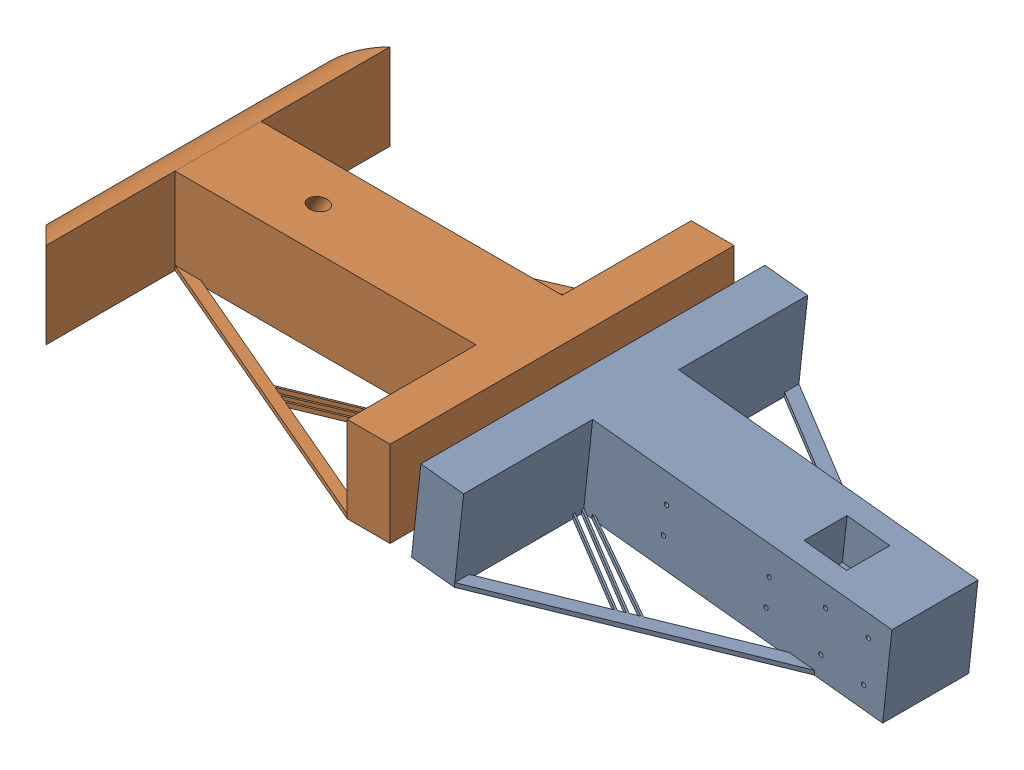
SolidWorks assembly Chassis_Assembly, configuration Default. Lengths in mm.
Overall size (1121.91 183.54 508).
5 component instances, 4 part files, 8 mates.
Components (placement in the parent):
- Go-Kart_ChassisP1V2-1: Go-Kart_ChassisP1V2 [Default] at (38.524 61.4151 0) x (0.994159 -0.107922 0) z (0 0 1) size (508 127 508)
- Go-Kart_ChassisP2V3-1: Go-Kart_ChassisP2V3 [Default] at (0 63.5 0) x (-1 0 0) z (0 0 -1) size (571.5 127 508)
- Go-Kart_Joint_V2-1: Go-Kart_Joint_V2 [Default] at (-88.9 63.5 0) size (120.65 95.38 31.75)
- Go-Kart_Joint_V2-2: Go-Kart_Joint_V2 [Default] at (126.9048 51.8209 0) x (-0.994159 0.107922 0) z (0 0 -1) size (120.65 95.38 31.75)
- Pin-1: Pin [Default] at (15.875 -0.127 0) size (31.75 31.75 38.1)
Mates (geometry in assembly coordinates):
- Coincident3: coincident aligned: circle of Go-Kart_ChassisP2V3-1; circle of Go-Kart_Joint_V2-1
- Coincident4: coincident aligned: circle of Go-Kart_ChassisP1V2-1; circle of Go-Kart_Joint_V2-2
- Coincident7: coincident anti-aligned: circle of Go-Kart_Joint_V2-2; circle of Pin-1
- Coincident8: coincident aligned: circle of Go-Kart_Joint_V2-1; circle of Pin-1
- Parallel3: parallel aligned: plane of Go-Kart_ChassisP1V2-1 through (94.8001 -8.567 254) normal (-0.107922 -0.994159 0); plane of Go-Kart_Joint_V2-2 through (36.8108 45.6328 -15.875) normal (-0.107922 -0.994159 0)
- Parallel4: parallel aligned: plane of Go-Kart_ChassisP2V3-1 through (-63.5 0 -254) normal (0 -1 0); plane of Go-Kart_Joint_V2-1 through (0 47.625 15.875) normal (0 -1 0)
- Coincident15: coincident anti-aligned: plane of Go-Kart_ChassisP2V3-1 through (-63.5 0 -254) normal (0 -1 0)
- Coincident16: coincident: point of Go-Kart_ChassisP2V3-1
